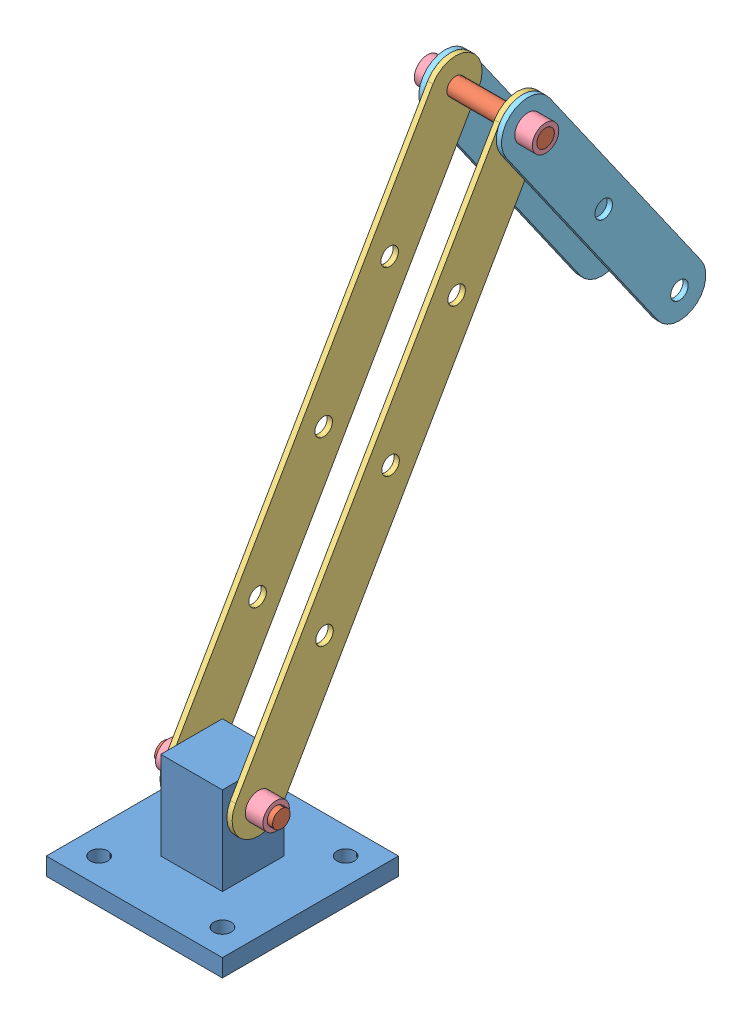
SolidWorks assembly Linkage Arm Assembly, configuration Default. Lengths in mm.
Overall size (100 325.7 306.93).
11 component instances, 5 part files, 24 mates.
Components (placement in the parent):
- Base Plate-1: Base Plate [Default] at (-93.2562 -64.6792 72.7706) size (100 60 100)
- Axle-1: Axle [Default] at (-93.2562 -19.6792 72.7706) x (1 0 0) z (0 0.076081 0.997102) size (67 10 10)
- 5-Hole Plate-1: 5-Hole Plate [Default] at (-75.7562 110.2246 -2.2294) x (1 0 0) z (0 -0.866025 0.5) size (3 30 330)
- 5-Hole Plate-2: 5-Hole Plate [Default] at (-110.7562 110.2246 -2.2294) x (-1 0 0) z (0 -0.866025 0.5) size (3 30 330)
- Sleeve-1: Sleeve [Default] at (-113.7562 -19.6792 72.7706) x (-1 0 0) z (0 -0.924225 -0.381849) size (10 15 15)
- Sleeve-2: Sleeve [Default] at (-62.7562 -19.6792 72.7706) x (-1 0 0) z (0 -0.760704 -0.649099) size (10 15 15)
- 3-Hole Plate-1: 3-Hole Plate [Default] at (-72.7562 178.692 -120.2477) x (1 0 0) z (0 0.819152 0.573576) size (3 30 180)
- 3-Hole Plate-2: 3-Hole Plate [Default] at (-116.7562 178.692 -120.2477) x (1 0 0) z (0 0.819152 0.573576) size (3 30 180)
- Sleeve-3: Sleeve [Default] at (-116.7562 240.1284 -77.2294) x (-1 0 0) z (0 -0.97983 0.199835) size (10 15 15)
- Axle-2: Axle [Default] at (-93.2562 240.1284 -77.2294) size (67 10 10)
- Sleeve-5: Sleeve [Default] at (-59.7562 240.1284 -77.2294) x (-1 0 0) z (0 0.924225 0.381849) size (10 15 15)
Mates (geometry in assembly coordinates):
- Coincident1: coincident aligned: plane of Base Plate-1 through (-93.2562 -64.6792 72.7706) normal (1 0 0); plane of Axle-1
- Concentric1: concentric anti-aligned: cylinder of Base Plate-1 through (-143.2562 -19.6792 72.7706) axis (1 0 0) radius 5; cylinder of Axle-1 through (-59.7562 -19.6792 72.7706) axis (-1 0 0) radius 5
- Concentric2: concentric anti-aligned: cylinder of Base Plate-1 through (-143.2562 -19.6792 72.7706) axis (1 0 0) radius 5; cylinder of 5-Hole Plate-1 through (-72.7562 -19.6792 72.7706) axis (-1 0 0) radius 5
- Coincident2: coincident anti-aligned: plane of Base Plate-1 through (-75.7562 -4.6792 90.2706) normal (1 0 0); plane of 5-Hole Plate-1 through (-75.7562 -19.6792 72.7706) normal (-1 0 0)
- Concentric3: concentric aligned: cylinder of Base Plate-1 through (-143.2562 -19.6792 72.7706) axis (1 0 0) radius 5; cylinder of 5-Hole Plate-2 through (-113.7562 -19.6792 72.7706) axis (1 0 0) radius 5
- Coincident3: coincident anti-aligned: plane of Base Plate-1 through (-110.7562 -4.6792 90.2706) normal (-1 0 0); plane of 5-Hole Plate-2 through (-110.7562 -19.6792 72.7706) normal (1 0 0)
- Parallel1: parallel aligned: plane of 5-Hole Plate-1 through (-72.7562 -12.1792 85.7609) normal (0 0.5 0.866025); plane of 5-Hole Plate-2 through (-113.7562 -12.1792 85.7609) normal (0 0.5 0.866025)
- Coincident5: coincident anti-aligned: plane of 5-Hole Plate-1 through (-72.7562 -19.6792 72.7706) normal (1 0 0); plane of Sleeve-2 through (-72.7562 -19.6792 72.7706) normal (-1 0 0)
- Concentric4: concentric anti-aligned: cylinder of Axle-1 through (-59.7562 -19.6792 72.7706) axis (-1 0 0) radius 5; cylinder of Sleeve-2 through (-72.7562 -19.6792 72.7706) axis (1 0 0) radius 5
- Coincident6: coincident anti-aligned: plane of 5-Hole Plate-2 through (-113.7562 -19.6792 72.7706) normal (-1 0 0); plane of Sleeve-1 through (-113.7562 -19.6792 72.7706) normal (1 0 0)
- Concentric5: concentric anti-aligned: cylinder of Axle-1 through (-59.7562 -19.6792 72.7706) axis (-1 0 0) radius 5; cylinder of Sleeve-1 through (-123.7562 -19.6792 72.7706) axis (1 0 0) radius 5
- Width1: width anti-aligned: plane of 5-Hole Plate-1 through (-72.7562 -19.6792 72.7706) normal (1 0 0); plane of 5-Hole Plate-2 through (-113.7562 -19.6792 72.7706) normal (-1 0 0); plane of Axle-2 through (-126.7562 240.1284 -77.2294) normal (-1 0 0); plane of Axle-2 through (-59.7562 240.1284 -77.2294) normal (1 0 0)
- Concentric6: concentric aligned: cylinder of 5-Hole Plate-1 through (-72.7562 240.1284 -77.2294) axis (-1 0 0) radius 5; cylinder of Axle-2 through (-59.7562 240.1284 -77.2294) axis (-1 0 0) radius 5
- Concentric7: concentric aligned: cylinder of 5-Hole Plate-1 through (-72.7562 240.1284 -77.2294) axis (-1 0 0) radius 5; cylinder of 3-Hole Plate-1 through (-69.7562 240.1284 -77.2294) axis (-1 0 0) radius 5
- Coincident7: coincident anti-aligned: plane of 5-Hole Plate-1 through (-72.7562 -19.6792 72.7706) normal (1 0 0); plane of 3-Hole Plate-1 through (-72.7562 240.1284 -77.2294) normal (-1 0 0)
- Concentric8: concentric anti-aligned: cylinder of 5-Hole Plate-2 through (-113.7562 240.1284 -77.2294) axis (1 0 0) radius 5; cylinder of 3-Hole Plate-2 through (-113.7562 240.1284 -77.2294) axis (-1 0 0) radius 5
- Coincident8: coincident anti-aligned: plane of 5-Hole Plate-2 through (-113.7562 -19.6792 72.7706) normal (-1 0 0); plane of 3-Hole Plate-2 through (-113.7562 240.1284 -77.2294) normal (1 0 0)
- Parallel2: parallel aligned: plane of 3-Hole Plate-1 through (-69.7562 248.732 -89.5167) normal (0 0.573576 -0.819152); plane of 3-Hole Plate-2 through (-113.7562 248.732 -89.5167) normal (0 0.573576 -0.819152)
- Concentric91: concentric anti-aligned: cylinder of 3-Hole Plate-1 through (-69.7562 240.1284 -77.2294) axis (-1 0 0) radius 5; cylinder of Sleeve-5 through (-69.7562 240.1284 -77.2294) axis (1 0 0) radius 5
- Coincident101: coincident anti-aligned: plane of 3-Hole Plate-1 through (-69.7562 240.1284 -77.2294) normal (1 0 0); plane of Sleeve-5 through (-69.7562 240.1284 -77.2294) normal (-1 0 0)
- Concentric10: concentric anti-aligned: cylinder of 3-Hole Plate-2 through (-113.7562 240.1284 -77.2294) axis (-1 0 0) radius 5; cylinder of Sleeve-3 through (-126.7562 240.1284 -77.2294) axis (1 0 0) radius 5
- Coincident11: coincident anti-aligned: plane of 3-Hole Plate-2 through (-116.7562 240.1284 -77.2294) normal (-1 0 0); plane of Sleeve-3 through (-116.7562 240.1284 -77.2294) normal (1 0 0)
- Angle1: planar angle = 0.523599 rad aligned: plane of Base Plate-1 through (-110.7562 -4.6792 90.2706) normal (0 0 1); plane of 5-Hole Plate-1 through (-72.7562 -12.1792 85.7609) normal (0 0.5 0.866025)
- Angle2: planar angle = 1.134464 rad anti-aligned: plane of 5-Hole Plate-1 through (-72.7562 -27.1792 59.7802) normal (0 -0.5 -0.866025); plane of 3-Hole Plate-1 through (-69.7562 231.5247 -64.9422) normal (0 -0.573576 0.819152)
